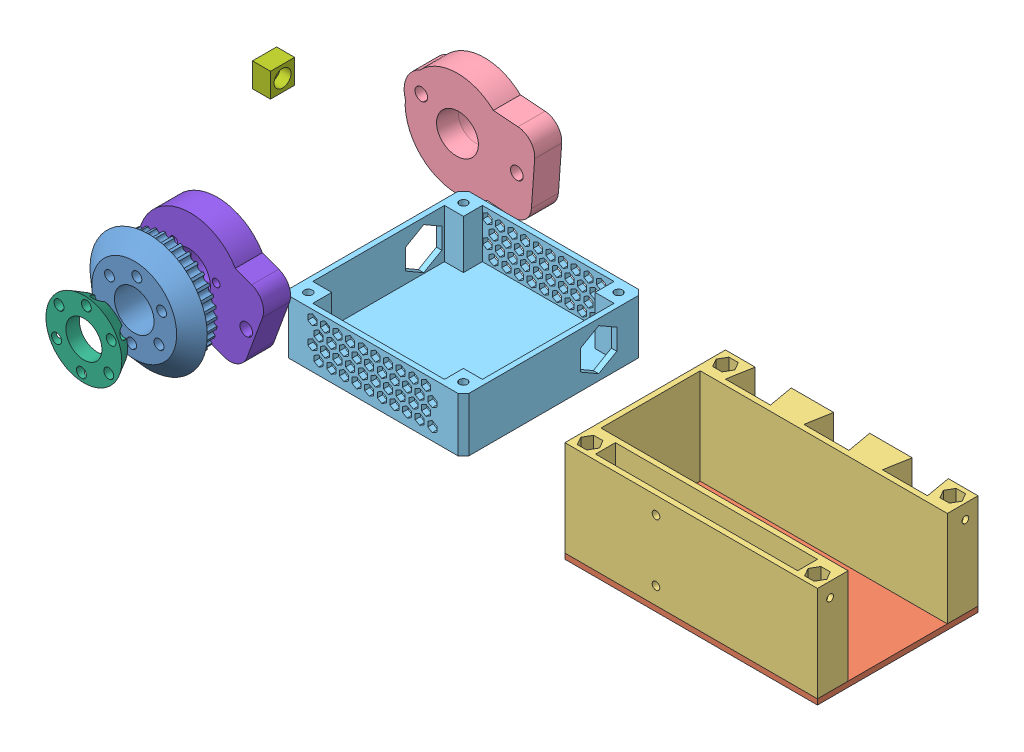
SolidWorks assembly Assem1, configuration Default. Lengths in mm.
Overall size (351.85 114.03 225.08).
8 component instances, 8 part files, 13 mates.
Components (placement in the parent):
- 36T HTD5 V2-1: 36T HTD5 V2 [Default] at (8.0646 36.8909 57.4226) x (1 0 0) z (0 1 0) size (65 18 65)
- Battery holder lid V1-1: Battery holder lid V1 [Default] at (232.8812 -27.7928 -26.3561) size (140 13 89)
- Battery holder V3-1: Battery holder V3 [Default] at (179.384 -27.7928 -18.9905) size (140 53 89)
- braket5-1: braket5 [Default] at (5.0759 28.9978 -126.7439) x (0.962163 0.272476 0) z (0 0 1) size (73.35 61.69 15.01)
- electronics box lid V1-1: electronics box lid V1 [Default] at (55.1619 -4.7928 -102.283) x (1 0 0) z (0 1 0) size (100 100 30)
- guide2-1: guide2 [Default] at (8.0646 36.8909 85.8406) x (0 1 0) z (1 0 0) size (42 7.92 42)
- king pin cap V1-1: king pin cap V1 [Default] at (-22.4677 76.5351 -47.3294) x (0 1 0) z (0 0 1) size (13.4 10 13.4)
- braket4-1: braket4 [Default] at (7.0073 37.9549 23.2561) x (0.999997 -0.002599 0) z (0 0 1) size (69.59 60.32 15.01)
Mates (geometry in assembly coordinates):
- Coincident1: coincident anti-aligned: plane of Battery holder lid V1-1 through (232.8812 -27.7928 -26.3561) normal (0 1 0); plane of Battery holder V3-1 through (179.384 -27.7928 -18.9905) normal (0 -1 0)
- Coincident2: coincident aligned: plane of Battery holder lid V1-1 through (179.384 -30.7928 -90.9905) normal (0 0 -1); plane of Battery holder V3-1 through (179.384 25.2072 -90.9905) normal (0 0 -1)
- Coincident3: coincident aligned: plane of Battery holder lid V1-1 through (319.384 -30.7928 -90.9905) normal (1 0 0); plane of Battery holder V3-1 through (319.384 25.2072 -18.9905) normal (1 0 0)
- Distance1: distance = 5 mm aligned: plane of electronics box lid V1-1 through (29.1308 -1.7928 -95.9905) normal (0 0 -1); plane of Battery holder V3-1 through (179.384 25.2072 -90.9905) normal (0 0 -1)
- Distance2: distance = 50.2531 mm anti-aligned: plane of electronics box lid V1-1 through (129.1308 -1.7928 -95.9905) normal (1 0 0); plane of Battery holder V3-1 through (179.384 25.2072 -18.9905) normal (-1 0 0)
- Coincident6: coincident aligned: plane of Battery holder V3-1 through (179.384 25.2072 -18.9905) normal (0 1 0); plane of electronics box lid V1-1 through (55.1619 25.2072 -102.283) normal (0 1 0)
- Concentric1: concentric anti-aligned: cylinder of 36T HTD5 V2-1 through (8.0646 36.8909 47.4226) axis (0 0 1) radius 11; cylinder of guide2-1 through (8.0646 36.8909 93.3407) axis (0 0 -1) radius 10
- Distance3: distance = 27.918 mm aligned: plane of guide2-1 through (8.0646 36.8909 93.3406) normal (0 0 1); plane of 36T HTD5 V2-1 through (8.0646 36.8909 65.4226) normal (0 0 1)
- Tangent3: tangent: cylinder of 36T HTD5 V2-1 through (8.0646 36.8909 47.4226) axis (0 0 1) radius 11; curve of braket4-1
- Distance4: distance = 39.1665 mm aligned: plane of braket4-1 through (7.0073 37.9549 18.2561) normal (0 0 -1); plane of 36T HTD5 V2-1 through (8.0646 36.8909 57.4226) normal (0 0 -1)
- Distance5: distance = 189.1665 mm aligned: plane of braket5-1 through (5.0759 28.9978 -131.7439) normal (0 0 -1); plane of 36T HTD5 V2-1 through (8.0646 36.8909 57.4226) normal (0 0 -1)
- Concentric2: concentric aligned: cylinder of braket5-1 through (-14.9926 38.0121 -116.7325) axis (0 0 -1) radius 3.5; cylinder of braket4-1 through (-14.9926 38.0121 33.2675) axis (0 0 -1) radius 3.5
- Concentric3: concentric aligned: cylinder of braket5-1 through (37.9877 26.5877 -57.7051) axis (0 0 -1) radius 3.5; cylinder of braket4-1 through (37.9877 26.5877 89.0128) axis (0 0 -1) radius 3.5
